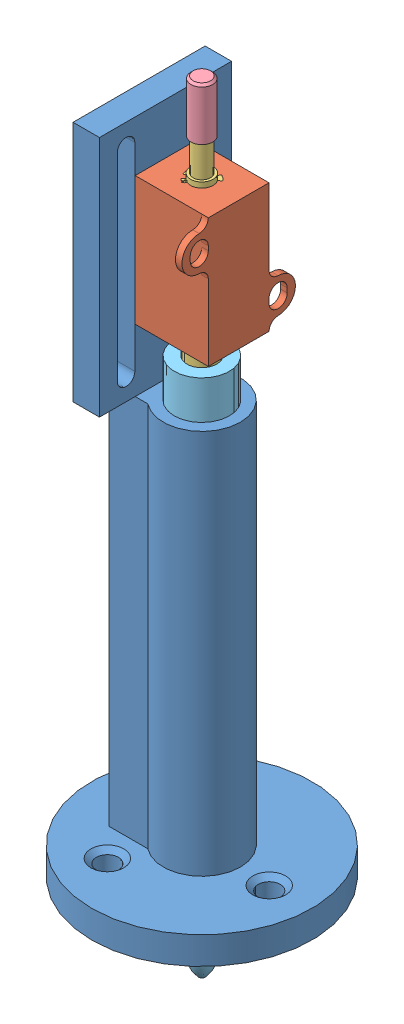
SolidWorks assembly PenHoldingAssembly, configuration Default. Lengths in mm.
Overall size (50.8 179.72 50.8).
6 component instances, 5 part files, 6 mates.
Components (placement in the parent):
- PenHolder-1: PenHolder [Default] at origin size (50.8 151.13 50.8)
- SolenoidAssembly-1: SolenoidAssembly [Default] at (37.7525 175.3273 13.5641) x (0 0 -1) z (-1 0 0) size (26.2 55.9 17)
  - Solenoid_Mount-2: Solenoid_Mount [Default] at (6.5641 46.5695 46.2525) x (1 0 0) z (0 0 -1) size (26.2 29.7 17)
  - Solenoid_Shaft-1: Solenoid_Shaft [Default] at (13.5641 0.2373 37.7525) x (-0.773677 0 0.63358) z (-0.63358 0 -0.773677) size (6.9 51.9 6.9)
  - Solenoid_Cap-1: Solenoid_Cap [Default] at (13.5641 -3.7627 37.7525) x (0.200587 0 -0.979676) z (0.979676 0 0.200587) size (5 12 5)
- 05_Pen-1: 05_Pen [Default] at (0 -0.635 0) x (0.983893 0 -0.178761) z (0.178761 0 0.983893) size (12.7 123.83 12.7)
Mates (geometry in assembly coordinates):
- Concentric1: concentric anti-aligned: cylinder of PenHolder-1 through (0 131.177 0) axis (0 1 0) radius 8.89; cylinder of SolenoidAssembly-1/Solenoid_Shaft-1 through (0 166.6375 0) axis (0 -1 0) radius 3.45
- Distance2: distance = 104.14 mm aligned: plane of PenHolder-1 through (6.35 19.05 0) normal (0 -1 0); plane of SolenoidAssembly-1/Solenoid_Shaft-1 through (-2.1859 123.19 2.6692) normal (0 -1 0)
- Concentric2: concentric aligned: cylinder of SolenoidAssembly-1/Solenoid_Shaft-1 through (0 166.6375 0) axis (0 -1 0) radius 3.45; cylinder of 05_Pen-1 through (0 -0.635 0) axis (0 -1 0) radius 6.35
- Coincident2: coincident anti-aligned: plane of SolenoidAssembly-1/Solenoid_Shaft-1 through (-2.1859 123.19 2.6692) normal (0 -1 0); plane of 05_Pen-1 through (0 123.19 0) normal (0 1 0)
- Parallel1: parallel anti-aligned: plane of SolenoidAssembly-1/Solenoid_Mount-2 through (8.5 128.7579 -7) normal (0 0 -1)
- Coincident4: coordinate: point of PenHolder-1
